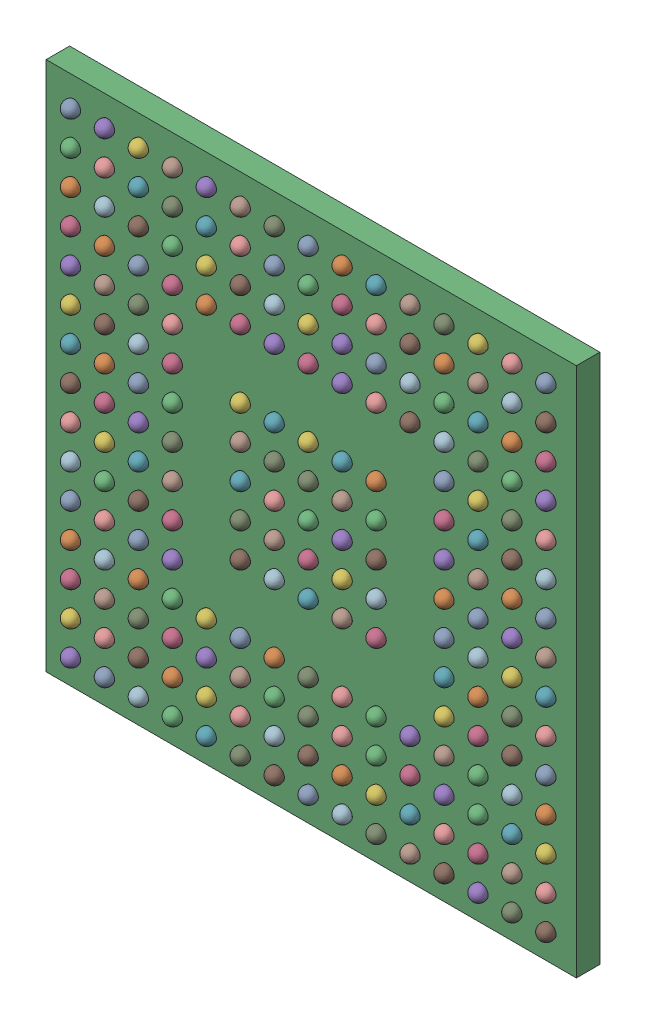
SolidWorks assembly U5, configuration Default. Lengths in mm.
Overall size (10.15 10.15 0.65).
406 component instances, 3 part files, 0 mates.
Components (placement in the parent):
- 1077123152-1: 1077123152 [Default] at (4.7211 42.5499 -1.744) x (1 0 0) z (0 0 -1) size (0.29 0.29 0.29)
  - Sphere-1: Sphere [Default] at origin size (0.29 0.29 0.29)
- 1077123152-2: 1077123152 [Default] at (4.7211 41.2499 -1.744) x (1 0 0) z (0 0 -1) size (0.29 0.29 0.29)
  - Sphere-1: Sphere [Default] at origin size (0.29 0.29 0.29)
- 1077123152-3: 1077123152 [Default] at (4.7211 41.8999 -1.744) x (1 0 0) z (0 0 -1) size (0.29 0.29 0.29)
  - Sphere-1: Sphere [Default] at origin size (0.29 0.29 0.29)
- 1077123152-4: 1077123152 [Default] at (4.7211 40.5999 -1.744) x (1 0 0) z (0 0 -1) size (0.29 0.29 0.29)
  - Sphere-1: Sphere [Default] at origin size (0.29 0.29 0.29)
- 1077123152-5: 1077123152 [Default] at (5.3711 42.55 -1.744) x (1 0 0) z (0 0 -1) size (0.29 0.29 0.29)
  - Sphere-1: Sphere [Default] at origin size (0.29 0.29 0.29)
- 1077123152-6: 1077123152 [Default] at (6.0211 42.55 -1.744) x (1 0 0) z (0 0 -1) size (0.29 0.29 0.29)
  - Sphere-1: Sphere [Default] at origin size (0.29 0.29 0.29)
- 1077123152-7: 1077123152 [Default] at (6.0211 41.8999 -1.744) x (1 0 0) z (0 0 -1) size (0.29 0.29 0.29)
  - Sphere-1: Sphere [Default] at origin size (0.29 0.29 0.29)
- 1077123152-8: 1077123152 [Default] at (6.6711 42.55 -1.744) x (1 0 0) z (0 0 -1) size (0.29 0.29 0.29)
  - Sphere-1: Sphere [Default] at origin size (0.29 0.29 0.29)
- 1077123152-9: 1077123152 [Default] at (6.6711 41.8999 -1.744) x (1 0 0) z (0 0 -1) size (0.29 0.29 0.29)
  - Sphere-1: Sphere [Default] at origin size (0.29 0.29 0.29)
- 1077123152-10: 1077123152 [Default] at (5.3711 41.8999 -1.744) x (1 0 0) z (0 0 -1) size (0.29 0.29 0.29)
  - Sphere-1: Sphere [Default] at origin size (0.29 0.29 0.29)
- 1077123152-11: 1077123152 [Default] at (6.0211 41.2499 -1.744) x (1 0 0) z (0 0 -1) size (0.29 0.29 0.29)
  - Sphere-1: Sphere [Default] at origin size (0.29 0.29 0.29)
- 1077123152-12: 1077123152 [Default] at (5.3711 41.2499 -1.744) x (1 0 0) z (0 0 -1) size (0.29 0.29 0.29)
  - Sphere-1: Sphere [Default] at origin size (0.29 0.29 0.29)
- 1077123152-13: 1077123152 [Default] at (6.0211 40.6 -1.744) x (1 0 0) z (0 0 -1) size (0.29 0.29 0.29)
  - Sphere-1: Sphere [Default] at origin size (0.29 0.29 0.29)
- 1077123152-14: 1077123152 [Default] at (5.3711 40.6 -1.744) x (1 0 0) z (0 0 -1) size (0.29 0.29 0.29)
  - Sphere-1: Sphere [Default] at origin size (0.29 0.29 0.29)
- 1077123152-15: 1077123152 [Default] at (6.6711 41.2499 -1.744) x (1 0 0) z (0 0 -1) size (0.29 0.29 0.29)
  - Sphere-1: Sphere [Default] at origin size (0.29 0.29 0.29)
- 1077123152-16: 1077123152 [Default] at (6.6711 40.6 -1.744) x (1 0 0) z (0 0 -1) size (0.29 0.29 0.29)
  - Sphere-1: Sphere [Default] at origin size (0.29 0.29 0.29)
- 1077123152-17: 1077123152 [Default] at (4.7211 39.9499 -1.744) x (1 0 0) z (0 0 -1) size (0.29 0.29 0.29)
  - Sphere-1: Sphere [Default] at origin size (0.29 0.29 0.29)
- 1077123152-18: 1077123152 [Default] at (4.7211 39.2999 -1.744) x (1 0 0) z (0 0 -1) size (0.29 0.29 0.29)
  - Sphere-1: Sphere [Default] at origin size (0.29 0.29 0.29)
- 1077123152-19: 1077123152 [Default] at (4.7211 38.6499 -1.744) x (1 0 0) z (0 0 -1) size (0.29 0.29 0.29)
  - Sphere-1: Sphere [Default] at origin size (0.29 0.29 0.29)
- 1077123152-20: 1077123152 [Default] at (5.3711 39.9499 -1.744) x (1 0 0) z (0 0 -1) size (0.29 0.29 0.29)
  - Sphere-1: Sphere [Default] at origin size (0.29 0.29 0.29)
- 1077123152-21: 1077123152 [Default] at (6.0211 39.9499 -1.744) x (1 0 0) z (0 0 -1) size (0.29 0.29 0.29)
  - Sphere-1: Sphere [Default] at origin size (0.29 0.29 0.29)
- 1077123152-22: 1077123152 [Default] at (6.6711 39.9499 -1.744) x (1 0 0) z (0 0 -1) size (0.29 0.29 0.29)
  - Sphere-1: Sphere [Default] at origin size (0.29 0.29 0.29)
- 1077123152-23: 1077123152 [Default] at (5.3711 39.2999 -1.744) x (1 0 0) z (0 0 -1) size (0.29 0.29 0.29)
  - Sphere-1: Sphere [Default] at origin size (0.29 0.29 0.29)
- 1077123152-24: 1077123152 [Default] at (6.0211 39.2999 -1.744) x (1 0 0) z (0 0 -1) size (0.29 0.29 0.29)
  - Sphere-1: Sphere [Default] at origin size (0.29 0.29 0.29)
- 1077123152-25: 1077123152 [Default] at (6.0211 38.6499 -1.744) x (1 0 0) z (0 0 -1) size (0.29 0.29 0.29)
  - Sphere-1: Sphere [Default] at origin size (0.29 0.29 0.29)
- 1077123152-26: 1077123152 [Default] at (5.3711 38.6499 -1.744) x (1 0 0) z (0 0 -1) size (0.29 0.29 0.29)
  - Sphere-1: Sphere [Default] at origin size (0.29 0.29 0.29)
- 1077123152-27: 1077123152 [Default] at (6.6711 38.6499 -1.744) x (1 0 0) z (0 0 -1) size (0.29 0.29 0.29)
  - Sphere-1: Sphere [Default] at origin size (0.29 0.29 0.29)
- 1077123152-28: 1077123152 [Default] at (6.6711 39.2999 -1.744) x (1 0 0) z (0 0 -1) size (0.29 0.29 0.29)
  - Sphere-1: Sphere [Default] at origin size (0.29 0.29 0.29)
- 1077123152-29: 1077123152 [Default] at (7.3211 42.55 -1.744) x (1 0 0) z (0 0 -1) size (0.29 0.29 0.29)
  - Sphere-1: Sphere [Default] at origin size (0.29 0.29 0.29)
- 1077123152-30: 1077123152 [Default] at (7.3211 41.2499 -1.744) x (1 0 0) z (0 0 -1) size (0.29 0.29 0.29)
  - Sphere-1: Sphere [Default] at origin size (0.29 0.29 0.29)
- 1077123152-31: 1077123152 [Default] at (7.3211 41.8999 -1.744) x (1 0 0) z (0 0 -1) size (0.29 0.29 0.29)
  - Sphere-1: Sphere [Default] at origin size (0.29 0.29 0.29)
- 1077123152-32: 1077123152 [Default] at (7.9711 42.55 -1.744) x (1 0 0) z (0 0 -1) size (0.29 0.29 0.29)
  - Sphere-1: Sphere [Default] at origin size (0.29 0.29 0.29)
- 1077123152-33: 1077123152 [Default] at (8.6211 42.55 -1.744) x (1 0 0) z (0 0 -1) size (0.29 0.29 0.29)
  - Sphere-1: Sphere [Default] at origin size (0.29 0.29 0.29)
- 1077123152-34: 1077123152 [Default] at (7.9711 41.8999 -1.744) x (1 0 0) z (0 0 -1) size (0.29 0.29 0.29)
  - Sphere-1: Sphere [Default] at origin size (0.29 0.29 0.29)
- 1077123152-35: 1077123152 [Default] at (7.9711 41.2499 -1.744) x (1 0 0) z (0 0 -1) size (0.29 0.29 0.29)
  - Sphere-1: Sphere [Default] at origin size (0.29 0.29 0.29)
- 1077123152-36: 1077123152 [Default] at (8.6211 41.2499 -1.744) x (1 0 0) z (0 0 -1) size (0.29 0.29 0.29)
  - Sphere-1: Sphere [Default] at origin size (0.29 0.29 0.29)
- 1077123152-37: 1077123152 [Default] at (8.6211 41.8999 -1.744) x (1 0 0) z (0 0 -1) size (0.29 0.29 0.29)
  - Sphere-1: Sphere [Default] at origin size (0.29 0.29 0.29)
- 1077123152-38: 1077123152 [Default] at (7.3211 40.6 -1.744) x (1 0 0) z (0 0 -1) size (0.29 0.29 0.29)
  - Sphere-1: Sphere [Default] at origin size (0.29 0.29 0.29)
- 1088887424-1: 1088887424 [Default] at (9.271 38 -2.244) size (10.15 10.15 0.45)
  - Extruded-20-1: Extruded-20 [Default] at origin size (10.15 10.15 0.45)
- 1077123152-39: 1077123152 [Default] at (7.9711 40.6 -1.744) x (1 0 0) z (0 0 -1) size (0.29 0.29 0.29)
  - Sphere-1: Sphere [Default] at origin size (0.29 0.29 0.29)
- 1077123152-40: 1077123152 [Default] at (8.6211 40.6 -1.744) x (1 0 0) z (0 0 -1) size (0.29 0.29 0.29)
  - Sphere-1: Sphere [Default] at origin size (0.29 0.29 0.29)
- 1077123152-41: 1077123152 [Default] at (7.9711 39.2999 -1.744) x (1 0 0) z (0 0 -1) size (0.29 0.29 0.29)
  - Sphere-1: Sphere [Default] at origin size (0.29 0.29 0.29)
- 1077123152-42: 1077123152 [Default] at (8.6211 39.2999 -1.744) x (1 0 0) z (0 0 -1) size (0.29 0.29 0.29)
  - Sphere-1: Sphere [Default] at origin size (0.29 0.29 0.29)
- 1077123152-43: 1077123152 [Default] at (7.9711 38.6499 -1.744) x (1 0 0) z (0 0 -1) size (0.29 0.29 0.29)
  - Sphere-1: Sphere [Default] at origin size (0.29 0.29 0.29)
- 1077123152-44: 1077123152 [Default] at (8.6211 38.6499 -1.744) x (1 0 0) z (0 0 -1) size (0.29 0.29 0.29)
  - Sphere-1: Sphere [Default] at origin size (0.29 0.29 0.29)
- 1077123152-45: 1077123152 [Default] at (4.7211 37.3499 -1.744) x (1 0 0) z (0 0 -1) size (0.29 0.29 0.29)
  - Sphere-1: Sphere [Default] at origin size (0.29 0.29 0.29)
- 1077123152-46: 1077123152 [Default] at (4.7211 37.9999 -1.744) x (1 0 0) z (0 0 -1) size (0.29 0.29 0.29)
  - Sphere-1: Sphere [Default] at origin size (0.29 0.29 0.29)
- 1077123152-47: 1077123152 [Default] at (4.7211 36.6999 -1.744) x (1 0 0) z (0 0 -1) size (0.29 0.29 0.29)
  - Sphere-1: Sphere [Default] at origin size (0.29 0.29 0.29)
- 1077123152-48: 1077123152 [Default] at (4.7211 36.0499 -1.744) x (1 0 0) z (0 0 -1) size (0.29 0.29 0.29)
  - Sphere-1: Sphere [Default] at origin size (0.29 0.29 0.29)
- 1077123152-49: 1077123152 [Default] at (4.7211 35.3999 -1.744) x (1 0 0) z (0 0 -1) size (0.29 0.29 0.29)
  - Sphere-1: Sphere [Default] at origin size (0.29 0.29 0.29)
- 1077123152-50: 1077123152 [Default] at (5.3711 36.6999 -1.744) x (1 0 0) z (0 0 -1) size (0.29 0.29 0.29)
  - Sphere-1: Sphere [Default] at origin size (0.29 0.29 0.29)
- 1077123152-51: 1077123152 [Default] at (5.3711 37.9999 -1.744) x (1 0 0) z (0 0 -1) size (0.29 0.29 0.29)
  - Sphere-1: Sphere [Default] at origin size (0.29 0.29 0.29)
- 1077123152-52: 1077123152 [Default] at (6.0211 37.9999 -1.744) x (1 0 0) z (0 0 -1) size (0.29 0.29 0.29)
  - Sphere-1: Sphere [Default] at origin size (0.29 0.29 0.29)
- 1077123152-53: 1077123152 [Default] at (5.3711 37.35 -1.744) x (1 0 0) z (0 0 -1) size (0.29 0.29 0.29)
  - Sphere-1: Sphere [Default] at origin size (0.29 0.29 0.29)
- 1077123152-54: 1077123152 [Default] at (6.0211 37.35 -1.744) x (1 0 0) z (0 0 -1) size (0.29 0.29 0.29)
  - Sphere-1: Sphere [Default] at origin size (0.29 0.29 0.29)
- 1077123152-55: 1077123152 [Default] at (6.6711 37.35 -1.744) x (1 0 0) z (0 0 -1) size (0.29 0.29 0.29)
  - Sphere-1: Sphere [Default] at origin size (0.29 0.29 0.29)
- 1077123152-56: 1077123152 [Default] at (6.6711 37.9999 -1.744) x (1 0 0) z (0 0 -1) size (0.29 0.29 0.29)
  - Sphere-1: Sphere [Default] at origin size (0.29 0.29 0.29)
- 1077123152-57: 1077123152 [Default] at (5.3711 36.0499 -1.744) x (1 0 0) z (0 0 -1) size (0.29 0.29 0.29)
  - Sphere-1: Sphere [Default] at origin size (0.29 0.29 0.29)
- 1077123152-58: 1077123152 [Default] at (6.0211 36.6999 -1.744) x (1 0 0) z (0 0 -1) size (0.29 0.29 0.29)
  - Sphere-1: Sphere [Default] at origin size (0.29 0.29 0.29)
- 1077123152-59: 1077123152 [Default] at (5.3711 35.3999 -1.744) x (1 0 0) z (0 0 -1) size (0.29 0.29 0.29)
  - Sphere-1: Sphere [Default] at origin size (0.29 0.29 0.29)
- 1077123152-60: 1077123152 [Default] at (6.0211 36.0499 -1.744) x (1 0 0) z (0 0 -1) size (0.29 0.29 0.29)
  - Sphere-1: Sphere [Default] at origin size (0.29 0.29 0.29)
- 1077123152-61: 1077123152 [Default] at (6.0211 35.3999 -1.744) x (1 0 0) z (0 0 -1) size (0.29 0.29 0.29)
  - Sphere-1: Sphere [Default] at origin size (0.29 0.29 0.29)
- 1077123152-62: 1077123152 [Default] at (6.6711 35.3999 -1.744) x (1 0 0) z (0 0 -1) size (0.29 0.29 0.29)
  - Sphere-1: Sphere [Default] at origin size (0.29 0.29 0.29)
- 1077123152-63: 1077123152 [Default] at (4.7211 34.7499 -1.744) x (1 0 0) z (0 0 -1) size (0.29 0.29 0.29)
  - Sphere-1: Sphere [Default] at origin size (0.29 0.29 0.29)
- 1077123152-64: 1077123152 [Default] at (4.7211 33.4499 -1.744) x (1 0 0) z (0 0 -1) size (0.29 0.29 0.29)
  - Sphere-1: Sphere [Default] at origin size (0.29 0.29 0.29)
- 1077123152-65: 1077123152 [Default] at (4.7211 34.0999 -1.744) x (1 0 0) z (0 0 -1) size (0.29 0.29 0.29)
  - Sphere-1: Sphere [Default] at origin size (0.29 0.29 0.29)
- 1737316336-1: 1737316336 [Default] at (4.7211 33.4499 -2.244) x (1 0 0) z (0 0 -1) size (0.5 0.5 0.01)
  - Cylinder-21-1: Cylinder-21 [Default] at origin size (0.5 0.5 0.01)
- 1077123152-66: 1077123152 [Default] at (5.3711 34.7499 -1.744) x (1 0 0) z (0 0 -1) size (0.29 0.29 0.29)
  - Sphere-1: Sphere [Default] at origin size (0.29 0.29 0.29)
- 1077123152-67: 1077123152 [Default] at (6.0211 34.7499 -1.744) x (1 0 0) z (0 0 -1) size (0.29 0.29 0.29)
  - Sphere-1: Sphere [Default] at origin size (0.29 0.29 0.29)
- 1077123152-68: 1077123152 [Default] at (5.3711 34.1 -1.744) x (1 0 0) z (0 0 -1) size (0.29 0.29 0.29)
  - Sphere-1: Sphere [Default] at origin size (0.29 0.29 0.29)
- 1077123152-69: 1077123152 [Default] at (6.0211 34.1 -1.744) x (1 0 0) z (0 0 -1) size (0.29 0.29 0.29)
  - Sphere-1: Sphere [Default] at origin size (0.29 0.29 0.29)
- 1077123152-70: 1077123152 [Default] at (6.0211 33.4499 -1.744) x (1 0 0) z (0 0 -1) size (0.29 0.29 0.29)
  - Sphere-1: Sphere [Default] at origin size (0.29 0.29 0.29)
- 1077123152-71: 1077123152 [Default] at (5.3711 33.4499 -1.744) x (1 0 0) z (0 0 -1) size (0.29 0.29 0.29)
  - Sphere-1: Sphere [Default] at origin size (0.29 0.29 0.29)
- 1077123152-72: 1077123152 [Default] at (6.6711 34.1 -1.744) x (1 0 0) z (0 0 -1) size (0.29 0.29 0.29)
  - Sphere-1: Sphere [Default] at origin size (0.29 0.29 0.29)
- 1077123152-73: 1077123152 [Default] at (6.6711 33.4499 -1.744) x (1 0 0) z (0 0 -1) size (0.29 0.29 0.29)
  - Sphere-1: Sphere [Default] at origin size (0.29 0.29 0.29)
- 1077123152-74: 1077123152 [Default] at (6.6711 36.6999 -1.744) x (1 0 0) z (0 0 -1) size (0.29 0.29 0.29)
  - Sphere-1: Sphere [Default] at origin size (0.29 0.29 0.29)
- 1077123152-75: 1077123152 [Default] at (6.6711 36.0499 -1.744) x (1 0 0) z (0 0 -1) size (0.29 0.29 0.29)
  - Sphere-1: Sphere [Default] at origin size (0.29 0.29 0.29)
- 1077123152-76: 1077123152 [Default] at (7.3211 35.3999 -1.744) x (1 0 0) z (0 0 -1) size (0.29 0.29 0.29)
  - Sphere-1: Sphere [Default] at origin size (0.29 0.29 0.29)
- 1077123152-77: 1077123152 [Default] at (7.9711 37.9999 -1.744) x (1 0 0) z (0 0 -1) size (0.29 0.29 0.29)
  - Sphere-1: Sphere [Default] at origin size (0.29 0.29 0.29)
- 1077123152-78: 1077123152 [Default] at (8.6211 37.35 -1.744) x (1 0 0) z (0 0 -1) size (0.29 0.29 0.29)
  - Sphere-1: Sphere [Default] at origin size (0.29 0.29 0.29)
- 1077123152-79: 1077123152 [Default] at (7.9711 37.35 -1.744) x (1 0 0) z (0 0 -1) size (0.29 0.29 0.29)
  - Sphere-1: Sphere [Default] at origin size (0.29 0.29 0.29)
- 1077123152-80: 1077123152 [Default] at (8.6211 37.9999 -1.744) x (1 0 0) z (0 0 -1) size (0.29 0.29 0.29)
  - Sphere-1: Sphere [Default] at origin size (0.29 0.29 0.29)
- 1077123152-81: 1077123152 [Default] at (7.9711 36.6999 -1.744) x (1 0 0) z (0 0 -1) size (0.29 0.29 0.29)
  - Sphere-1: Sphere [Default] at origin size (0.29 0.29 0.29)
- 1077123152-82: 1077123152 [Default] at (8.6211 36.6999 -1.744) x (1 0 0) z (0 0 -1) size (0.29 0.29 0.29)
  - Sphere-1: Sphere [Default] at origin size (0.29 0.29 0.29)
- 1077123152-83: 1077123152 [Default] at (7.9711 35.3999 -1.744) x (1 0 0) z (0 0 -1) size (0.29 0.29 0.29)
  - Sphere-1: Sphere [Default] at origin size (0.29 0.29 0.29)
- 1077123152-84: 1077123152 [Default] at (8.6211 35.3999 -1.744) x (1 0 0) z (0 0 -1) size (0.29 0.29 0.29)
  - Sphere-1: Sphere [Default] at origin size (0.29 0.29 0.29)
- 1077123152-85: 1077123152 [Default] at (8.6211 34.7499 -1.744) x (1 0 0) z (0 0 -1) size (0.29 0.29 0.29)
  - Sphere-1: Sphere [Default] at origin size (0.29 0.29 0.29)
- 1077123152-86: 1077123152 [Default] at (6.6711 34.7499 -1.744) x (1 0 0) z (0 0 -1) size (0.29 0.29 0.29)
  - Sphere-1: Sphere [Default] at origin size (0.29 0.29 0.29)
- 1077123152-87: 1077123152 [Default] at (7.3211 34.7499 -1.744) x (1 0 0) z (0 0 -1) size (0.29 0.29 0.29)
  - Sphere-1: Sphere [Default] at origin size (0.29 0.29 0.29)
- 1077123152-88: 1077123152 [Default] at (7.3211 34.1 -1.744) x (1 0 0) z (0 0 -1) size (0.29 0.29 0.29)
  - Sphere-1: Sphere [Default] at origin size (0.29 0.29 0.29)
- 1077123152-89: 1077123152 [Default] at (7.3211 33.4499 -1.744) x (1 0 0) z (0 0 -1) size (0.29 0.29 0.29)
  - Sphere-1: Sphere [Default] at origin size (0.29 0.29 0.29)
- 1077123152-90: 1077123152 [Default] at (7.9711 34.7499 -1.744) x (1 0 0) z (0 0 -1) size (0.29 0.29 0.29)
  - Sphere-1: Sphere [Default] at origin size (0.29 0.29 0.29)
- 1077123152-91: 1077123152 [Default] at (7.9711 33.4499 -1.744) x (1 0 0) z (0 0 -1) size (0.29 0.29 0.29)
  - Sphere-1: Sphere [Default] at origin size (0.29 0.29 0.29)
- 1077123152-92: 1077123152 [Default] at (7.9711 34.1 -1.744) x (1 0 0) z (0 0 -1) size (0.29 0.29 0.29)
  - Sphere-1: Sphere [Default] at origin size (0.29 0.29 0.29)
- 1077123152-93: 1077123152 [Default] at (8.6211 33.4499 -1.744) x (1 0 0) z (0 0 -1) size (0.29 0.29 0.29)
  - Sphere-1: Sphere [Default] at origin size (0.29 0.29 0.29)
- 1077123152-94: 1077123152 [Default] at (8.6211 34.1 -1.744) x (1 0 0) z (0 0 -1) size (0.29 0.29 0.29)
  - Sphere-1: Sphere [Default] at origin size (0.29 0.29 0.29)
- 1077123152-95: 1077123152 [Default] at (9.2711 42.55 -1.744) x (1 0 0) z (0 0 -1) size (0.29 0.29 0.29)
  - Sphere-1: Sphere [Default] at origin size (0.29 0.29 0.29)
- 1077123152-96: 1077123152 [Default] at (9.9211 42.55 -1.744) x (1 0 0) z (0 0 -1) size (0.29 0.29 0.29)
  - Sphere-1: Sphere [Default] at origin size (0.29 0.29 0.29)
- 1077123152-97: 1077123152 [Default] at (9.2711 41.8999 -1.744) x (1 0 0) z (0 0 -1) size (0.29 0.29 0.29)
  - Sphere-1: Sphere [Default] at origin size (0.29 0.29 0.29)
- 1077123152-98: 1077123152 [Default] at (9.9211 41.8999 -1.744) x (1 0 0) z (0 0 -1) size (0.29 0.29 0.29)
  - Sphere-1: Sphere [Default] at origin size (0.29 0.29 0.29)
- 1077123152-99: 1077123152 [Default] at (9.9211 41.2499 -1.744) x (1 0 0) z (0 0 -1) size (0.29 0.29 0.29)
  - Sphere-1: Sphere [Default] at origin size (0.29 0.29 0.29)
- 1077123152-100: 1077123152 [Default] at (9.2711 41.2499 -1.744) x (1 0 0) z (0 0 -1) size (0.29 0.29 0.29)
  - Sphere-1: Sphere [Default] at origin size (0.29 0.29 0.29)
- 1077123152-101: 1077123152 [Default] at (10.5711 42.55 -1.744) x (1 0 0) z (0 0 -1) size (0.29 0.29 0.29)
  - Sphere-1: Sphere [Default] at origin size (0.29 0.29 0.29)
- 1077123152-102: 1077123152 [Default] at (11.2211 42.55 -1.744) x (1 0 0) z (0 0 -1) size (0.29 0.29 0.29)
  - Sphere-1: Sphere [Default] at origin size (0.29 0.29 0.29)
- 1077123152-103: 1077123152 [Default] at (11.8711 42.55 -1.744) x (1 0 0) z (0 0 -1) size (0.29 0.29 0.29)
  - Sphere-1: Sphere [Default] at origin size (0.29 0.29 0.29)
- 1077123152-104: 1077123152 [Default] at (10.5711 41.8999 -1.744) x (1 0 0) z (0 0 -1) size (0.29 0.29 0.29)
  - Sphere-1: Sphere [Default] at origin size (0.29 0.29 0.29)
- 1077123152-105: 1077123152 [Default] at (11.2211 41.8999 -1.744) x (1 0 0) z (0 0 -1) size (0.29 0.29 0.29)
  - Sphere-1: Sphere [Default] at origin size (0.29 0.29 0.29)
- 1077123152-106: 1077123152 [Default] at (11.2211 41.2499 -1.744) x (1 0 0) z (0 0 -1) size (0.29 0.29 0.29)
  - Sphere-1: Sphere [Default] at origin size (0.29 0.29 0.29)
- 1077123152-107: 1077123152 [Default] at (10.5711 41.2499 -1.744) x (1 0 0) z (0 0 -1) size (0.29 0.29 0.29)
  - Sphere-1: Sphere [Default] at origin size (0.29 0.29 0.29)
- 1077123152-108: 1077123152 [Default] at (11.8711 41.8999 -1.744) x (1 0 0) z (0 0 -1) size (0.29 0.29 0.29)
  - Sphere-1: Sphere [Default] at origin size (0.29 0.29 0.29)
- 1077123152-109: 1077123152 [Default] at (11.8711 41.2499 -1.744) x (1 0 0) z (0 0 -1) size (0.29 0.29 0.29)
  - Sphere-1: Sphere [Default] at origin size (0.29 0.29 0.29)
- 1077123152-110: 1077123152 [Default] at (9.2711 40.6 -1.744) x (1 0 0) z (0 0 -1) size (0.29 0.29 0.29)
  - Sphere-1: Sphere [Default] at origin size (0.29 0.29 0.29)
- 1077123152-111: 1077123152 [Default] at (9.9211 40.6 -1.744) x (1 0 0) z (0 0 -1) size (0.29 0.29 0.29)
  - Sphere-1: Sphere [Default] at origin size (0.29 0.29 0.29)
- 1077123152-112: 1077123152 [Default] at (9.2711 39.2999 -1.744) x (1 0 0) z (0 0 -1) size (0.29 0.29 0.29)
  - Sphere-1: Sphere [Default] at origin size (0.29 0.29 0.29)
- 1077123152-113: 1077123152 [Default] at (9.9211 39.2999 -1.744) x (1 0 0) z (0 0 -1) size (0.29 0.29 0.29)
  - Sphere-1: Sphere [Default] at origin size (0.29 0.29 0.29)
- 1077123152-114: 1077123152 [Default] at (9.9211 38.6499 -1.744) x (1 0 0) z (0 0 -1) size (0.29 0.29 0.29)
  - Sphere-1: Sphere [Default] at origin size (0.29 0.29 0.29)
- 1077123152-115: 1077123152 [Default] at (9.2711 38.6499 -1.744) x (1 0 0) z (0 0 -1) size (0.29 0.29 0.29)
  - Sphere-1: Sphere [Default] at origin size (0.29 0.29 0.29)
- 1077123152-116: 1077123152 [Default] at (10.5711 40.6 -1.744) x (1 0 0) z (0 0 -1) size (0.29 0.29 0.29)
  - Sphere-1: Sphere [Default] at origin size (0.29 0.29 0.29)
- 1077123152-117: 1077123152 [Default] at (11.2211 40.6 -1.744) x (1 0 0) z (0 0 -1) size (0.29 0.29 0.29)
  - Sphere-1: Sphere [Default] at origin size (0.29 0.29 0.29)
- 1077123152-118: 1077123152 [Default] at (11.8711 40.6 -1.744) x (1 0 0) z (0 0 -1) size (0.29 0.29 0.29)
  - Sphere-1: Sphere [Default] at origin size (0.29 0.29 0.29)
- 1077123152-119: 1077123152 [Default] at (11.8711 39.9499 -1.744) x (1 0 0) z (0 0 -1) size (0.29 0.29 0.29)
  - Sphere-1: Sphere [Default] at origin size (0.29 0.29 0.29)
- 1077123152-120: 1077123152 [Default] at (10.5711 39.2999 -1.744) x (1 0 0) z (0 0 -1) size (0.29 0.29 0.29)
  - Sphere-1: Sphere [Default] at origin size (0.29 0.29 0.29)
- 1077123152-121: 1077123152 [Default] at (10.5711 38.6499 -1.744) x (1 0 0) z (0 0 -1) size (0.29 0.29 0.29)
  - Sphere-1: Sphere [Default] at origin size (0.29 0.29 0.29)
- 1077123152-122: 1077123152 [Default] at (11.8711 39.2999 -1.744) x (1 0 0) z (0 0 -1) size (0.29 0.29 0.29)
  - Sphere-1: Sphere [Default] at origin size (0.29 0.29 0.29)
- 1077123152-123: 1077123152 [Default] at (11.8711 38.6499 -1.744) x (1 0 0) z (0 0 -1) size (0.29 0.29 0.29)
  - Sphere-1: Sphere [Default] at origin size (0.29 0.29 0.29)
- 1077123152-124: 1077123152 [Default] at (12.5211 42.55 -1.744) x (1 0 0) z (0 0 -1) size (0.29 0.29 0.29)
  - Sphere-1: Sphere [Default] at origin size (0.29 0.29 0.29)
- 1077123152-125: 1077123152 [Default] at (12.5211 41.2499 -1.744) x (1 0 0) z (0 0 -1) size (0.29 0.29 0.29)
  - Sphere-1: Sphere [Default] at origin size (0.29 0.29 0.29)
- 1077123152-126: 1077123152 [Default] at (12.5211 41.8999 -1.744) x (1 0 0) z (0 0 -1) size (0.29 0.29 0.29)
  - Sphere-1: Sphere [Default] at origin size (0.29 0.29 0.29)
- 1077123152-127: 1077123152 [Default] at (12.5211 40.6 -1.744) x (1 0 0) z (0 0 -1) size (0.29 0.29 0.29)
  - Sphere-1: Sphere [Default] at origin size (0.29 0.29 0.29)
- 1077123152-128: 1077123152 [Default] at (13.1711 42.55 -1.744) x (1 0 0) z (0 0 -1) size (0.29 0.29 0.29)
  - Sphere-1: Sphere [Default] at origin size (0.29 0.29 0.29)
- 1077123152-129: 1077123152 [Default] at (13.8211 41.8999 -1.744) x (1 0 0) z (0 0 -1) size (0.29 0.29 0.29)
  - Sphere-1: Sphere [Default] at origin size (0.29 0.29 0.29)
- 1077123152-130: 1077123152 [Default] at (13.1711 41.8999 -1.744) x (1 0 0) z (0 0 -1) size (0.29 0.29 0.29)
  - Sphere-1: Sphere [Default] at origin size (0.29 0.29 0.29)
- 1077123152-131: 1077123152 [Default] at (13.8211 42.55 -1.744) x (1 0 0) z (0 0 -1) size (0.29 0.29 0.29)
  - Sphere-1: Sphere [Default] at origin size (0.29 0.29 0.29)
- 1077123152-132: 1077123152 [Default] at (13.1711 41.2499 -1.744) x (1 0 0) z (0 0 -1) size (0.29 0.29 0.29)
  - Sphere-1: Sphere [Default] at origin size (0.29 0.29 0.29)
- 1077123152-133: 1077123152 [Default] at (13.1711 40.6 -1.744) x (1 0 0) z (0 0 -1) size (0.29 0.29 0.29)
  - Sphere-1: Sphere [Default] at origin size (0.29 0.29 0.29)
- 1077123152-134: 1077123152 [Default] at (13.8211 41.2499 -1.744) x (1 0 0) z (0 0 -1) size (0.29 0.29 0.29)
  - Sphere-1: Sphere [Default] at origin size (0.29 0.29 0.29)
- 1077123152-135: 1077123152 [Default] at (13.8211 40.6 -1.744) x (1 0 0) z (0 0 -1) size (0.29 0.29 0.29)
  - Sphere-1: Sphere [Default] at origin size (0.29 0.29 0.29)
- 1077123152-136: 1077123152 [Default] at (12.5211 39.9499 -1.744) x (1 0 0) z (0 0 -1) size (0.29 0.29 0.29)
  - Sphere-1: Sphere [Default] at origin size (0.29 0.29 0.29)
- 1077123152-137: 1077123152 [Default] at (12.5211 39.2999 -1.744) x (1 0 0) z (0 0 -1) size (0.29 0.29 0.29)
  - Sphere-1: Sphere [Default] at origin size (0.29 0.29 0.29)
- 1077123152-138: 1077123152 [Default] at (12.5211 38.6499 -1.744) x (1 0 0) z (0 0 -1) size (0.29 0.29 0.29)
  - Sphere-1: Sphere [Default] at origin size (0.29 0.29 0.29)
- 1077123152-139: 1077123152 [Default] at (13.1711 39.9499 -1.744) x (1 0 0) z (0 0 -1) size (0.29 0.29 0.29)
  - Sphere-1: Sphere [Default] at origin size (0.29 0.29 0.29)
- 1077123152-140: 1077123152 [Default] at (13.8211 39.9499 -1.744) x (1 0 0) z (0 0 -1) size (0.29 0.29 0.29)
  - Sphere-1: Sphere [Default] at origin size (0.29 0.29 0.29)
- 1077123152-141: 1077123152 [Default] at (13.1711 39.2999 -1.744) x (1 0 0) z (0 0 -1) size (0.29 0.29 0.29)
  - Sphere-1: Sphere [Default] at origin size (0.29 0.29 0.29)
- 1077123152-142: 1077123152 [Default] at (13.8211 39.2999 -1.744) x (1 0 0) z (0 0 -1) size (0.29 0.29 0.29)
  - Sphere-1: Sphere [Default] at origin size (0.29 0.29 0.29)
- 1077123152-143: 1077123152 [Default] at (13.8211 38.6499 -1.744) x (1 0 0) z (0 0 -1) size (0.29 0.29 0.29)
  - Sphere-1: Sphere [Default] at origin size (0.29 0.29 0.29)
- 1077123152-144: 1077123152 [Default] at (13.1711 38.6499 -1.744) x (1 0 0) z (0 0 -1) size (0.29 0.29 0.29)
  - Sphere-1: Sphere [Default] at origin size (0.29 0.29 0.29)
- 1077123152-145: 1077123152 [Default] at (9.2711 37.9999 -1.744) x (1 0 0) z (0 0 -1) size (0.29 0.29 0.29)
  - Sphere-1: Sphere [Default] at origin size (0.29 0.29 0.29)
- 1077123152-146: 1077123152 [Default] at (9.2711 37.35 -1.744) x (1 0 0) z (0 0 -1) size (0.29 0.29 0.29)
  - Sphere-1: Sphere [Default] at origin size (0.29 0.29 0.29)
- 1077123152-147: 1077123152 [Default] at (9.9211 37.9999 -1.744) x (1 0 0) z (0 0 -1) size (0.29 0.29 0.29)
  - Sphere-1: Sphere [Default] at origin size (0.29 0.29 0.29)
- 1077123152-148: 1077123152 [Default] at (9.9211 37.35 -1.744) x (1 0 0) z (0 0 -1) size (0.29 0.29 0.29)
  - Sphere-1: Sphere [Default] at origin size (0.29 0.29 0.29)
- 1077123152-149: 1077123152 [Default] at (9.2711 36.6999 -1.744) x (1 0 0) z (0 0 -1) size (0.29 0.29 0.29)
  - Sphere-1: Sphere [Default] at origin size (0.29 0.29 0.29)
- 1077123152-150: 1077123152 [Default] at (9.9211 36.6999 -1.744) x (1 0 0) z (0 0 -1) size (0.29 0.29 0.29)
  - Sphere-1: Sphere [Default] at origin size (0.29 0.29 0.29)
- 1077123152-151: 1077123152 [Default] at (9.2711 35.3999 -1.744) x (1 0 0) z (0 0 -1) size (0.29 0.29 0.29)
  - Sphere-1: Sphere [Default] at origin size (0.29 0.29 0.29)
- 1077123152-152: 1077123152 [Default] at (9.9211 35.3999 -1.744) x (1 0 0) z (0 0 -1) size (0.29 0.29 0.29)
  - Sphere-1: Sphere [Default] at origin size (0.29 0.29 0.29)
- 1077123152-153: 1077123152 [Default] at (10.5711 37.9999 -1.744) x (1 0 0) z (0 0 -1) size (0.29 0.29 0.29)
  - Sphere-1: Sphere [Default] at origin size (0.29 0.29 0.29)
- 1077123152-154: 1077123152 [Default] at (10.5711 37.35 -1.744) x (1 0 0) z (0 0 -1) size (0.29 0.29 0.29)
  - Sphere-1: Sphere [Default] at origin size (0.29 0.29 0.29)
- 1077123152-155: 1077123152 [Default] at (11.8711 37.35 -1.744) x (1 0 0) z (0 0 -1) size (0.29 0.29 0.29)
  - Sphere-1: Sphere [Default] at origin size (0.29 0.29 0.29)
- 1077123152-156: 1077123152 [Default] at (11.8711 37.9999 -1.744) x (1 0 0) z (0 0 -1) size (0.29 0.29 0.29)
  - Sphere-1: Sphere [Default] at origin size (0.29 0.29 0.29)
- 1077123152-157: 1077123152 [Default] at (10.5711 35.3999 -1.744) x (1 0 0) z (0 0 -1) size (0.29 0.29 0.29)
  - Sphere-1: Sphere [Default] at origin size (0.29 0.29 0.29)
- 1077123152-158: 1077123152 [Default] at (10.5711 36.6999 -1.744) x (1 0 0) z (0 0 -1) size (0.29 0.29 0.29)
  - Sphere-1: Sphere [Default] at origin size (0.29 0.29 0.29)
- 1077123152-159: 1077123152 [Default] at (11.2211 35.3999 -1.744) x (1 0 0) z (0 0 -1) size (0.29 0.29 0.29)
  - Sphere-1: Sphere [Default] at origin size (0.29 0.29 0.29)
- 1077123152-160: 1077123152 [Default] at (11.8711 36.0499 -1.744) x (1 0 0) z (0 0 -1) size (0.29 0.29 0.29)
  - Sphere-1: Sphere [Default] at origin size (0.29 0.29 0.29)
- 1077123152-161: 1077123152 [Default] at (11.8711 36.6999 -1.744) x (1 0 0) z (0 0 -1) size (0.29 0.29 0.29)
  - Sphere-1: Sphere [Default] at origin size (0.29 0.29 0.29)
- 1077123152-162: 1077123152 [Default] at (11.8711 35.3999 -1.744) x (1 0 0) z (0 0 -1) size (0.29 0.29 0.29)
  - Sphere-1: Sphere [Default] at origin size (0.29 0.29 0.29)
- 1077123152-163: 1077123152 [Default] at (9.2711 34.7499 -1.744) x (1 0 0) z (0 0 -1) size (0.29 0.29 0.29)
  - Sphere-1: Sphere [Default] at origin size (0.29 0.29 0.29)
- 1077123152-164: 1077123152 [Default] at (9.9211 34.7499 -1.744) x (1 0 0) z (0 0 -1) size (0.29 0.29 0.29)
  - Sphere-1: Sphere [Default] at origin size (0.29 0.29 0.29)
- 1077123152-165: 1077123152 [Default] at (9.2711 34.1 -1.744) x (1 0 0) z (0 0 -1) size (0.29 0.29 0.29)
  - Sphere-1: Sphere [Default] at origin size (0.29 0.29 0.29)
- 1077123152-166: 1077123152 [Default] at (9.9211 33.4499 -1.744) x (1 0 0) z (0 0 -1) size (0.29 0.29 0.29)
  - Sphere-1: Sphere [Default] at origin size (0.29 0.29 0.29)
- 1077123152-167: 1077123152 [Default] at (9.2711 33.4499 -1.744) x (1 0 0) z (0 0 -1) size (0.29 0.29 0.29)
  - Sphere-1: Sphere [Default] at origin size (0.29 0.29 0.29)
- 1077123152-168: 1077123152 [Default] at (9.9211 34.1 -1.744) x (1 0 0) z (0 0 -1) size (0.29 0.29 0.29)
  - Sphere-1: Sphere [Default] at origin size (0.29 0.29 0.29)
- 1077123152-169: 1077123152 [Default] at (10.5711 34.7499 -1.744) x (1 0 0) z (0 0 -1) size (0.29 0.29 0.29)
  - Sphere-1: Sphere [Default] at origin size (0.29 0.29 0.29)
- 1077123152-170: 1077123152 [Default] at (11.2211 34.7499 -1.744) x (1 0 0) z (0 0 -1) size (0.29 0.29 0.29)
  - Sphere-1: Sphere [Default] at origin size (0.29 0.29 0.29)
- 1077123152-171: 1077123152 [Default] at (11.8711 34.7499 -1.744) x (1 0 0) z (0 0 -1) size (0.29 0.29 0.29)
  - Sphere-1: Sphere [Default] at origin size (0.29 0.29 0.29)
- 1077123152-172: 1077123152 [Default] at (10.5711 34.1 -1.744) x (1 0 0) z (0 0 -1) size (0.29 0.29 0.29)
  - Sphere-1: Sphere [Default] at origin size (0.29 0.29 0.29)
- 1077123152-173: 1077123152 [Default] at (11.2211 34.1 -1.744) x (1 0 0) z (0 0 -1) size (0.29 0.29 0.29)
  - Sphere-1: Sphere [Default] at origin size (0.29 0.29 0.29)
- 1077123152-174: 1077123152 [Default] at (11.2211 33.4499 -1.744) x (1 0 0) z (0 0 -1) size (0.29 0.29 0.29)
  - Sphere-1: Sphere [Default] at origin size (0.29 0.29 0.29)
- 1077123152-175: 1077123152 [Default] at (10.5711 33.4499 -1.744) x (1 0 0) z (0 0 -1) size (0.29 0.29 0.29)
  - Sphere-1: Sphere [Default] at origin size (0.29 0.29 0.29)
- 1077123152-176: 1077123152 [Default] at (11.8711 34.1 -1.744) x (1 0 0) z (0 0 -1) size (0.29 0.29 0.29)
  - Sphere-1: Sphere [Default] at origin size (0.29 0.29 0.29)
- 1077123152-177: 1077123152 [Default] at (11.8711 33.4499 -1.744) x (1 0 0) z (0 0 -1) size (0.29 0.29 0.29)
  - Sphere-1: Sphere [Default] at origin size (0.29 0.29 0.29)
- 1077123152-178: 1077123152 [Default] at (12.5211 37.35 -1.744) x (1 0 0) z (0 0 -1) size (0.29 0.29 0.29)
  - Sphere-1: Sphere [Default] at origin size (0.29 0.29 0.29)
- 1077123152-179: 1077123152 [Default] at (12.5211 37.9999 -1.744) x (1 0 0) z (0 0 -1) size (0.29 0.29 0.29)
  - Sphere-1: Sphere [Default] at origin size (0.29 0.29 0.29)
- 1077123152-180: 1077123152 [Default] at (12.5211 36.6999 -1.744) x (1 0 0) z (0 0 -1) size (0.29 0.29 0.29)
  - Sphere-1: Sphere [Default] at origin size (0.29 0.29 0.29)
- 1077123152-181: 1077123152 [Default] at (12.5211 35.3999 -1.744) x (1 0 0) z (0 0 -1) size (0.29 0.29 0.29)
  - Sphere-1: Sphere [Default] at origin size (0.29 0.29 0.29)
- 1077123152-182: 1077123152 [Default] at (12.5211 36.0499 -1.744) x (1 0 0) z (0 0 -1) size (0.29 0.29 0.29)
  - Sphere-1: Sphere [Default] at origin size (0.29 0.29 0.29)
- 1077123152-183: 1077123152 [Default] at (13.1711 37.9999 -1.744) x (1 0 0) z (0 0 -1) size (0.29 0.29 0.29)
  - Sphere-1: Sphere [Default] at origin size (0.29 0.29 0.29)
- 1077123152-184: 1077123152 [Default] at (13.1711 37.35 -1.744) x (1 0 0) z (0 0 -1) size (0.29 0.29 0.29)
  - Sphere-1: Sphere [Default] at origin size (0.29 0.29 0.29)
- 1077123152-185: 1077123152 [Default] at (13.8211 37.35 -1.744) x (1 0 0) z (0 0 -1) size (0.29 0.29 0.29)
  - Sphere-1: Sphere [Default] at origin size (0.29 0.29 0.29)
- 1077123152-186: 1077123152 [Default] at (13.8211 37.9999 -1.744) x (1 0 0) z (0 0 -1) size (0.29 0.29 0.29)
  - Sphere-1: Sphere [Default] at origin size (0.29 0.29 0.29)
- 1077123152-187: 1077123152 [Default] at (13.1711 36.6999 -1.744) x (1 0 0) z (0 0 -1) size (0.29 0.29 0.29)
  - Sphere-1: Sphere [Default] at origin size (0.29 0.29 0.29)
- 1077123152-188: 1077123152 [Default] at (13.8211 36.6999 -1.744) x (1 0 0) z (0 0 -1) size (0.29 0.29 0.29)
  - Sphere-1: Sphere [Default] at origin size (0.29 0.29 0.29)
- 1077123152-189: 1077123152 [Default] at (13.1711 36.0499 -1.744) x (1 0 0) z (0 0 -1) size (0.29 0.29 0.29)
  - Sphere-1: Sphere [Default] at origin size (0.29 0.29 0.29)
- 1077123152-190: 1077123152 [Default] at (13.1711 35.3999 -1.744) x (1 0 0) z (0 0 -1) size (0.29 0.29 0.29)
  - Sphere-1: Sphere [Default] at origin size (0.29 0.29 0.29)
- 1077123152-191: 1077123152 [Default] at (13.8211 36.0499 -1.744) x (1 0 0) z (0 0 -1) size (0.29 0.29 0.29)
  - Sphere-1: Sphere [Default] at origin size (0.29 0.29 0.29)
- 1077123152-192: 1077123152 [Default] at (13.8211 35.3999 -1.744) x (1 0 0) z (0 0 -1) size (0.29 0.29 0.29)
  - Sphere-1: Sphere [Default] at origin size (0.29 0.29 0.29)
- 1077123152-193: 1077123152 [Default] at (12.5211 34.7499 -1.744) x (1 0 0) z (0 0 -1) size (0.29 0.29 0.29)
  - Sphere-1: Sphere [Default] at origin size (0.29 0.29 0.29)
- 1077123152-194: 1077123152 [Default] at (12.5211 34.1 -1.744) x (1 0 0) z (0 0 -1) size (0.29 0.29 0.29)
  - Sphere-1: Sphere [Default] at origin size (0.29 0.29 0.29)
- 1077123152-195: 1077123152 [Default] at (12.5211 33.4499 -1.744) x (1 0 0) z (0 0 -1) size (0.29 0.29 0.29)
  - Sphere-1: Sphere [Default] at origin size (0.29 0.29 0.29)
- 1077123152-196: 1077123152 [Default] at (13.8211 34.7499 -1.744) x (1 0 0) z (0 0 -1) size (0.29 0.29 0.29)
  - Sphere-1: Sphere [Default] at origin size (0.29 0.29 0.29)
- 1077123152-197: 1077123152 [Default] at (13.1711 34.7499 -1.744) x (1 0 0) z (0 0 -1) size (0.29 0.29 0.29)
  - Sphere-1: Sphere [Default] at origin size (0.29 0.29 0.29)
- 1077123152-198: 1077123152 [Default] at (13.1711 34.1 -1.744) x (1 0 0) z (0 0 -1) size (0.29 0.29 0.29)
  - Sphere-1: Sphere [Default] at origin size (0.29 0.29 0.29)
- 1077123152-199: 1077123152 [Default] at (13.1711 33.4499 -1.744) x (1 0 0) z (0 0 -1) size (0.29 0.29 0.29)
  - Sphere-1: Sphere [Default] at origin size (0.29 0.29 0.29)
- 1077123152-200: 1077123152 [Default] at (13.8211 34.1 -1.744) x (1 0 0) z (0 0 -1) size (0.29 0.29 0.29)
  - Sphere-1: Sphere [Default] at origin size (0.29 0.29 0.29)
- 1077123152-201: 1077123152 [Default] at (13.8211 33.4499 -1.744) x (1 0 0) z (0 0 -1) size (0.29 0.29 0.29)
  - Sphere-1: Sphere [Default] at origin size (0.29 0.29 0.29)
